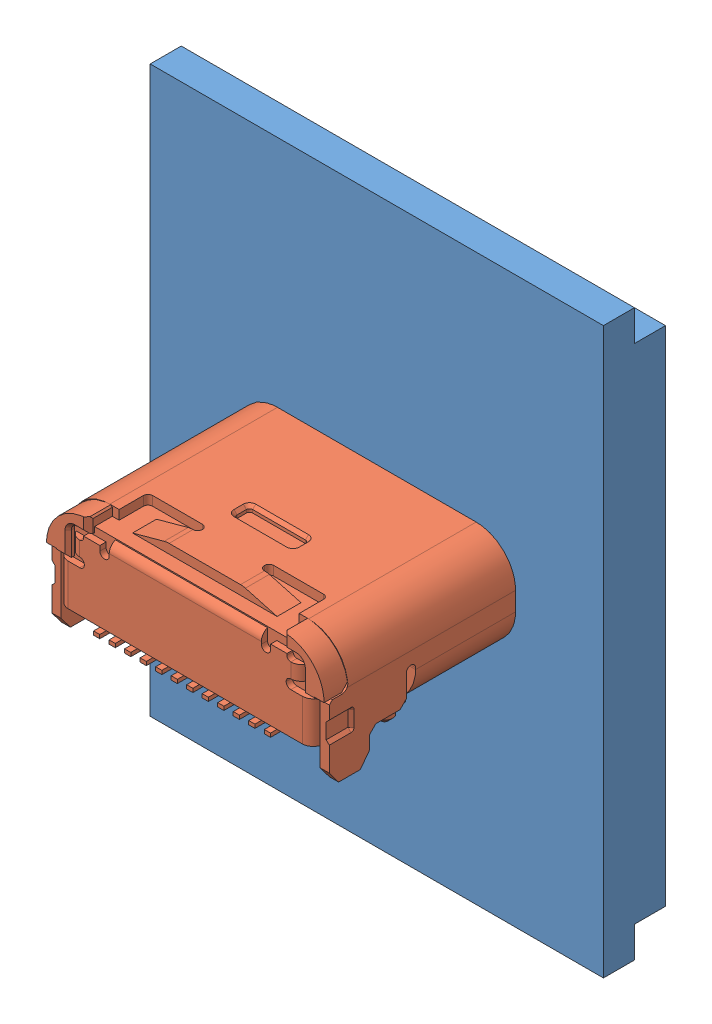
SolidWorks assembly Keystone-USB-C, configuration Standard. Lengths in mm.
Overall size (14.6 18.2 8.17).
2 component instances, 2 part files, 3 mates.
Components (placement in the parent):
- Keystone-USB-C-Pannel-1: Keystone-USB-C-Pannel [Standard] at (1.5605 -4.7888 17.2) size (14.6 18.2 2)
- USB-C-1: USB-C [Standard] at (-5.7395 3.3112 21.9) x (-1 0 0) z (0 0 -1) size (8.94 3.77 8.17)
Mates (geometry in assembly coordinates):
- Deckungsgleich1: coincident aligned: plane of Keystone-USB-C-Pannel-1 through (1.5605 -4.7888 17.2) normal (0 0 -1); plane of USB-C-1 through (-2.5395 -14.8987 17.2) normal (0 0 -1)
- Deckungsgleich2: coincident anti-aligned: plane of Keystone-USB-C-Pannel-1 through (-10.2095 3.6112 27.2) normal (1 0 0); plane of USB-C-1 through (-10.2095 3.6112 25.2) normal (-1 0 0)
- Deckungsgleich3: coincident anti-aligned: plane of Keystone-USB-C-Pannel-1 through (-2.5395 4.8812 27.2) normal (0 -1 0); plane of USB-C-1 through (-2.5395 4.8812 25.2) normal (0 1 0)
